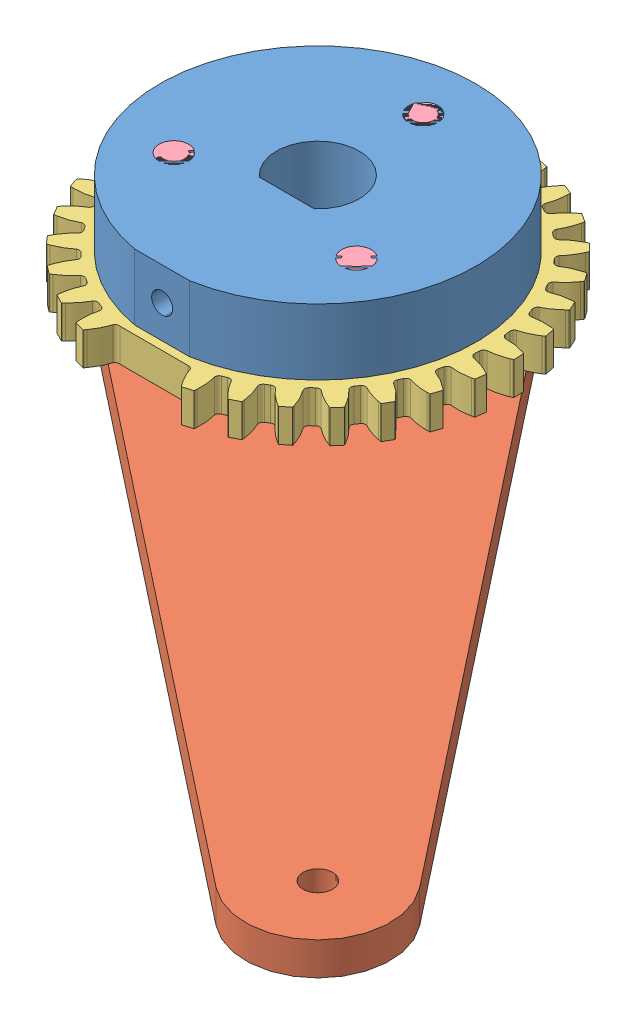
SolidWorks assembly arm_upper_complete, configuration Default. Lengths in mm.
Overall size (88.08 14.2 88.05).
6 component instances, 4 part files, 12 mates.
Components (placement in the parent):
- arm_collar-1: arm_collar [Default] at (13.5599 -1.2214 -6.3255) size (30.48 6.35 30.25)
- arm_upper-1: arm_upper [Default] at (13.5599 -7.5714 -6.3255) x (-0.707107 0 -0.707107) z (0 1 0) size (92.08 30.48 3.17)
- gear_stepper-1: gear_stepper [Default] at (13.5599 -4.3964 -6.3255) x (-0.959493 0 0.281733) z (0 1 0) size (37.03 37 3.17)
- 4-40_12_screw-1: 4-40_12_screw [Default] at (4.761 5.1286 -1.2455) x (0.952213 0 0.305436) z (0.305436 0 -0.952213) size (5.41 14.2 5.41)
- 4-40_12_screw-2: 4-40_12_screw [Default] at (22.3587 5.1286 -1.2455) x (0.806013 0 0.591898) z (0.591898 0 -0.806013) size (5.41 14.2 5.41)
- 4-40_12_screw-3: 4-40_12_screw [Default] at (13.5599 5.1286 -16.4855) x (-0.35728 0 0.933997) z (0.933997 0 0.35728) size (5.41 14.2 5.41)
Mates (geometry in assembly coordinates):
- Coincident1: coincident: plane of arm_collar-1 through (13.5599 -1.2214 -6.3255) normal (0 -1 0); plane of gear_stepper-1 through (18.1939 -1.2214 11.4345) normal (0 1 0)
- Coincident4: coincident anti-aligned: plane of arm_upper-1 through (62.9513 -4.3964 43.0659) normal (0 1 0); plane of gear_stepper-1 through (18.1939 -4.3964 11.4345) normal (0 -1 0)
- Coincident6: coincident aligned: plane of arm_collar-1 through (10.9141 5.1286 -3.3255) normal (0 0 -1); plane of gear_stepper-1 through (16.2056 -1.2214 -3.3255) normal (0 0 -1)
- Coincident7: coincident aligned: plane of arm_collar-1 through (10.9141 5.1286 -3.3255) normal (0 0 -1); plane of arm_upper-1 through (10.9141 -4.3964 -3.3255) normal (0 0 -1)
- Concentric1: concentric aligned: cylinder of arm_collar-1 through (13.5599 5.1286 -6.3255) axis (0 -1 0) radius 4; cylinder of gear_stepper-1 through (13.5599 -1.2214 -6.3255) axis (0 -1 0) radius 4
- Concentric2: concentric aligned: cylinder of arm_upper-1 through (13.5599 -4.3964 -6.3255) axis (0 -1 0) radius 4; cylinder of gear_stepper-1 through (13.5599 -1.2214 -6.3255) axis (0 -1 0) radius 4
- Concentric5: concentric anti-aligned: cylinder of arm_upper-1 through (22.3587 -4.3964 -1.2455) axis (0 -1 0) radius 1.524; cylinder of 4-40_12_screw-2 through (22.3587 52.0656 -1.2455) axis (0 -1 0) radius 1.4224
- Concentric6: concentric anti-aligned: cylinder of arm_upper-1 through (13.5599 -4.3964 -16.4855) axis (0 -1 0) radius 1.524; cylinder of 4-40_12_screw-3 through (13.5599 -7.5714 -16.4855) axis (0 1 0) radius 1.4224
- Concentric7: concentric anti-aligned: cylinder of arm_upper-1 through (4.761 -4.3964 -1.2455) axis (0 -1 0) radius 1.524; cylinder of 4-40_12_screw-1 through (4.761 -7.5714 -1.2455) axis (0 1 0) radius 1.4224
- Coincident11: coincident anti-aligned: plane of arm_upper-1 through (62.9513 -7.5714 43.0659) normal (0 -1 0); plane of 4-40_12_screw-1 through (4.761 -7.5714 -1.2455) normal (0 1 0)
- Coincident12: coincident anti-aligned: plane of arm_upper-1 through (62.9513 -7.5714 43.0659) normal (0 -1 0); plane of 4-40_12_screw-3 through (13.5599 -7.5714 -16.4855) normal (0 1 0)
- Coincident13: coincident anti-aligned: plane of arm_upper-1 through (62.9513 -7.5714 43.0659) normal (0 -1 0); plane of 4-40_12_screw-2 through (22.3587 -7.5714 -1.2455) normal (0 1 0)
